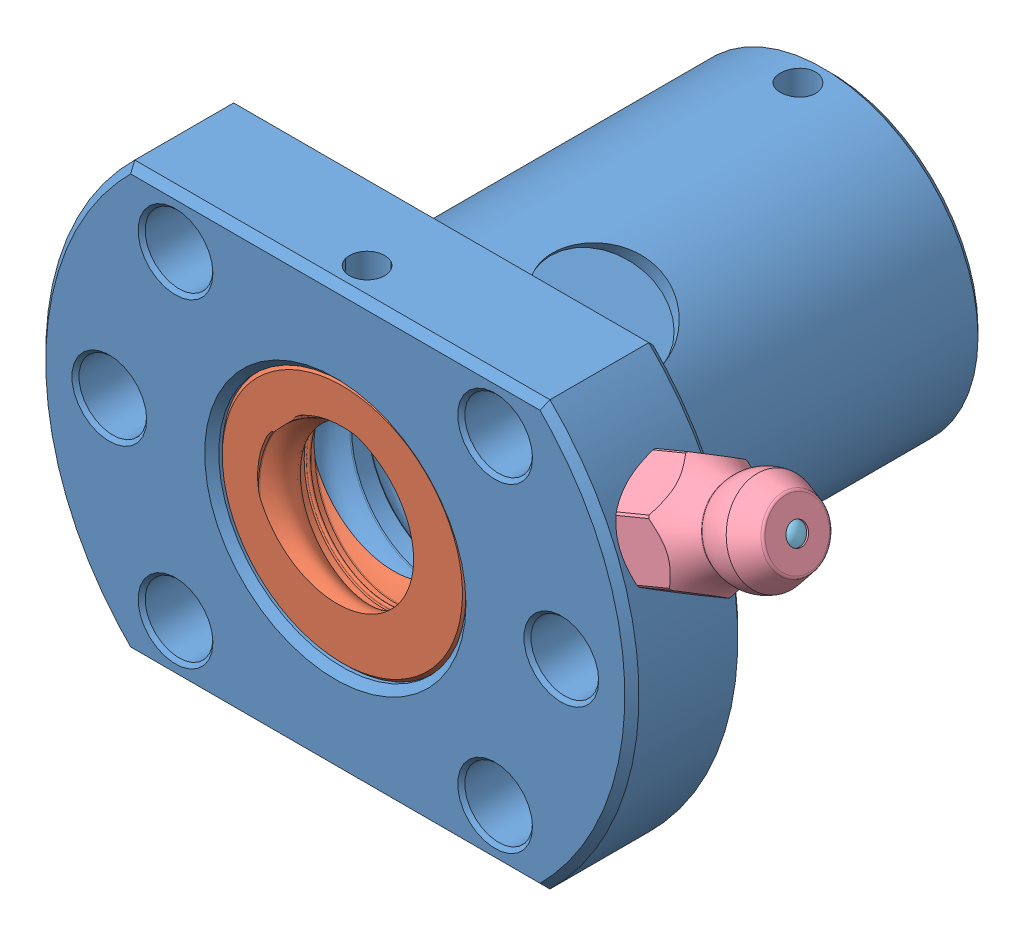
SolidWorks assembly SFU1204-3, configuration Default. Lengths in mm.
Overall size (51.14 30.68 39.46).
10 component instances, 7 part files, 21 mates.
Components (placement in the parent):
- SFU Ball Nut-1: SFU Ball Nut [1204-3] at origin
- SFU1204 Washer Front-1: SFU1204 Washer Front [Default] at origin
- SFU1204 Washer Back-1: SFU1204 Washer Back [Default] at origin
- Grease Nipple A M6x1.00-2: Grease Nipple A M6x1.00 [Default] at (26.2888 10.8892 -4.25) x (0.382683 -0.92388 0) z (0 0 1) size (8.34 16.1 7)
  - Grease Nipple A-1: Grease Nipple A [A M6x1.00] at origin
  - Steel Ball-1: Steel Ball [Ø 2.50] at (0 1.1952 0)
- ISO 4027 - M3 x 5-C-1: ISO 4027 - M3 x 5-C [ISO 4027 - M3 x 5-C] at (0 13.75 -2.25) x (0 -1 0) z (-1 0 0)
- ISO 4027 - M3 x 5-C-2: ISO 4027 - M3 x 5-C [ISO 4027 - M3 x 5-C] at (0 -13.75 -2.25) x (0 1 0) z (-1 0 0)
- ISO 4027 - M3 x 2.5-C-3: ISO 4027 - M3 x 2.5-C [ISO 4027 - M3 x 2.5-C] at (0 11.25 -32.75) x (0 -1 0) z (1 0 0)
- ISO 4027 - M3 x 2.5-C-4: ISO 4027 - M3 x 2.5-C [ISO 4027 - M3 x 2.5-C] at (0 -11.25 -32.75) x (0 1 0) z (1 0 0)
Mates (geometry in assembly coordinates):
- Concentric1: concentric aligned: cylinder of SFU Ball Nut-1 through (0 0 0) axis (0 0 1) radius 8.75; cylinder of SFU1204 Washer Front-1 through (0 0 -4.5) axis (0 0 1) radius 8.75
- Coincident1: coincident anti-aligned: plane of SFU Ball Nut-1 through (6.25 0 -4.5) normal (0 0 1); plane of SFU1204 Washer Front-1 through (0 0 -4.5) normal (0 0 -1)
- Parallel1: parallel aligned: plane of SFU Ball Nut-1 through (0 0 0) normal (0 1 0); plane of SFU1204 Washer Front-1 through (0 0 0) normal (0 1 0)
- Concentric2: concentric aligned: cylinder of SFU Ball Nut-1 through (0 0 0) axis (0 0 1) radius 8.75; cylinder of SFU1204 Washer Back-1 through (0 0 -34.5) axis (0 0 1) radius 8.75
- Coincident2: coincident anti-aligned: plane of SFU Ball Nut-1 through (8.75 0 -30.5) normal (0 0 -1); plane of SFU1204 Washer Back-1 through (0 0 -30.5) normal (0 0 1)
- Parallel2: parallel aligned: plane of SFU Ball Nut-1 through (0 0 0) normal (0 1 0); plane of SFU1204 Washer Back-1 through (0 0 0) normal (0 1 0)
- Concentric8: concentric aligned: cylinder of SFU Ball Nut-1 through (0 15 -2.25) axis (0 1 0) radius 1.25; cylinder of ISO 4027 - M3 x 5-C-1 through (0 26.45 -2.25) axis (0 1 0) radius 1.5
- Concentric9: concentric anti-aligned: cylinder of SFU Ball Nut-1 through (0 15 -2.25) axis (0 1 0) radius 1.25; cylinder of ISO 4027 - M3 x 5-C-2 through (0 -26.45 -2.25) axis (0 -1 0) radius 1.5
- Concentric10: concentric aligned: cylinder of SFU Ball Nut-1 through (0 15 -32.75) axis (0 1 0) radius 1.25; cylinder of ISO 4027 - M3 x 2.5-C-3 through (0 23.95 -32.75) axis (0 1 0) radius 1.5
- Concentric11: concentric anti-aligned: cylinder of SFU Ball Nut-1 through (0 15 -32.75) axis (0 1 0) radius 1.25; cylinder of ISO 4027 - M3 x 2.5-C-4 through (0 -23.95 -32.75) axis (0 -1 0) radius 1.5
- Coincident3: coincident: cylinder of SFU1204 Washer Front-1 through (0 0 -4.5) axis (0 0 1) radius 8.75; point of ISO 4027 - M3 x 5-C-1
- Coincident4: coincident: cylinder of SFU1204 Washer Front-1 through (0 0 -4.5) axis (0 0 1) radius 8.75; point of ISO 4027 - M3 x 5-C-2
- Coincident5: coincident: cylinder of SFU1204 Washer Back-1 through (0 0 -34.5) axis (0 0 1) radius 8.75; point of ISO 4027 - M3 x 2.5-C-4
- Coincident6: coincident: cylinder of SFU1204 Washer Back-1 through (0 0 -34.5) axis (0 0 1) radius 8.75; point of ISO 4027 - M3 x 2.5-C-3
- Parallel4: parallel aligned: plane of SFU Ball Nut-1 through (0 0 0) normal (0 0 1); plane of ISO 4027 - M3 x 5-C-1 through (0 13.75 -2.25) normal (0 0 1)
- Parallel5: parallel anti-aligned: plane of SFU Ball Nut-1 through (0 0 0) normal (0 0 1); plane of ISO 4027 - M3 x 5-C-2 through (0 -13.75 -2.25) normal (0 0 -1)
- Parallel6: parallel anti-aligned: plane of SFU Ball Nut-1 through (0 0 0) normal (0 0 1); plane of ISO 4027 - M3 x 2.5-C-3 through (0 11.25 -32.75) normal (0 0 -1)
- Parallel7: parallel aligned: plane of SFU Ball Nut-1 through (0 0 0) normal (0 0 1); plane of ISO 4027 - M3 x 2.5-C-4 through (0 -11.25 -32.75) normal (0 0 1)
- Concentric13: concentric anti-aligned: cylinder of SFU Ball Nut-1 through (19.4015 8.0364 -4.25) axis (0.92388 0.382683 0) radius 2.5; cylinder of Grease Nipple A M6x1.00-2/Grease Nipple A-1 through (2.8474 1.1794 -4.25) axis (-0.92388 -0.382683 0) radius 1.25
- Tangent3: tangent anti-aligned: cylinder of SFU Ball Nut-1 through (0 0 0) axis (0 0 1) radius 21; plane of Grease Nipple A M6x1.00-2/Grease Nipple A-1 through (20.9289 4.3487 -4.25) normal (-0.92388 -0.382683 0)
- Parallel8: parallel aligned: plane of SFU Ball Nut-1 through (0 0 0) normal (0 0 1); plane of Grease Nipple A M6x1.00-2 through (26.2888 10.8892 -4.25) normal (0 0 1)
